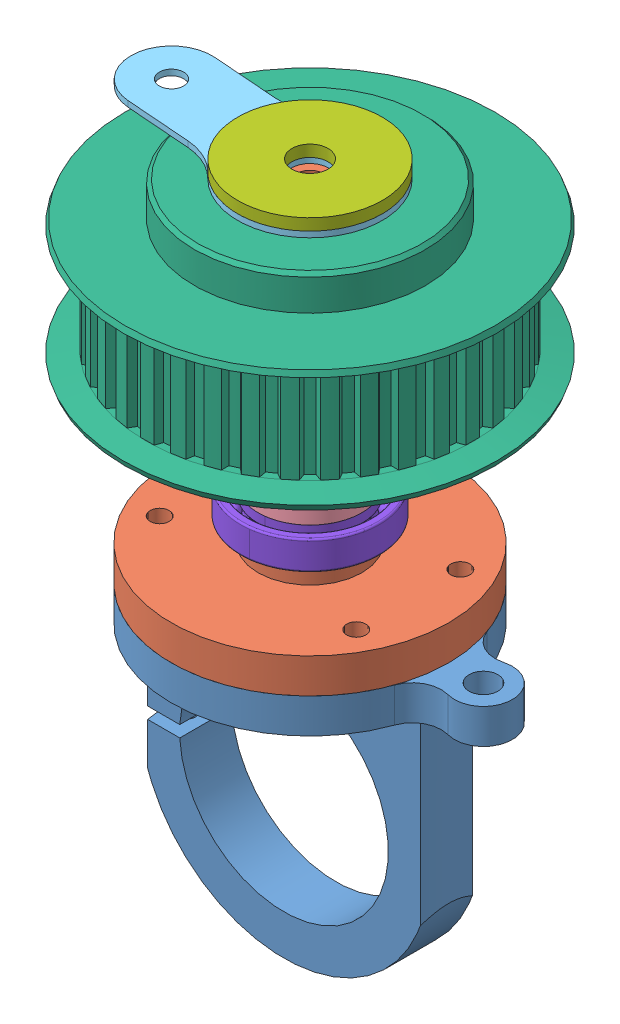
SolidWorks assembly B Axis, configuration Défaut. Lengths in mm.
Overall size (68.86 117.5 64.68).
9 component instances, 8 part files, 22 mates.
Components (placement in the parent):
- Spindle Housing v2-1: Spindle Housing v2 [Défaut] at (0 23 0) x (1 0 0) z (0 -1 0) size (59.51 48 54)
- B Axis-1: B Axis [Défaut] at (0 35 0) x (1 0 0) z (0 1 0) size (48 48 60)
- Bague B Axis_4.5mm v-2-1: Bague B Axis_4.5mm v-2 [Défaut] at (0 62.5 0) x (0.999992 0 -0.004028) z (0 -1 0) size (18 18 6.5)
- Bague Entretoise B axis bearing-1: Bague Entretoise B axis bearing [Défaut] at (0 51 0) x (0.946789 0 -0.321855) z (0 -1 0) size (18 18 7)
- Cale Axe B-1: Cale Axe B [Défaut] at (0 90.5 0) x (0.997118 0 0.075871) z (0 -1 0) size (45.5 25 1)
- pulley B Axis-1: pulley B Axis [Default] at (0 62.5 0) x (0 1 0) z (0 0 1) size (27 64.68 64.68)
- Rondelle B axis v-2-1: Rondelle B axis v-2 [Défaut] at (0 92.5 0) x (-0.97461 0 -0.223907) z (0 -1 0) size (25 25 2)
- 61802-1: 61802 [Défaut] at (0 44 0) x (0 -1 0) z (0.118563 0 0.992946) size (5 24 24)
- 61802-2: 61802 [Défaut] at (0 56 0) x (0 -1 0) z (-0.147702 0 0.989032) size (5 24 24)
Mates (geometry in assembly coordinates):
- Coincident6: coincident: plane of ? through (83.3313 -30.816 57.0781) normal (0 0 -1); plane of ? through (83.3313 -40.416 57.0781) normal (0 0 1)
- Coaxiale20: concentric anti-aligned: cylinder of Spindle Housing v2-1 through (0 29 0) axis (0 -1 0) radius 24; cylinder of B Axis-1 through (0 29 0) axis (0 1 0) radius 24
- Coïncidente11: coincident anti-aligned: plane of Spindle Housing v2-1 through (0 29 0) normal (0 1 0); plane of B Axis-1 through (0 29 0) normal (0 -1 0)
- Coaxiale21: concentric aligned: cylinder of B Axis-1 through (0 89 0) axis (0 -1 0) radius 7.5; cylinder of 61802-1 through (0 -56 0) axis (0 -1 0) radius 7.5
- Coaxiale22: concentric aligned: cylinder of B Axis-1 through (0 89 0) axis (0 -1 0) radius 7.5; cylinder of 61802-2 through (0 -44 0) axis (0 -1 0) radius 7.5
- Coaxiale23: concentric anti-aligned: cylinder of B Axis-1 through (0 89 0) axis (0 -1 0) radius 7.5; cylinder of Bague B Axis_4.5mm v-2-1 through (0 56 0) axis (0 1 0) radius 9
- Coaxiale24: concentric anti-aligned: cylinder of B Axis-1 through (0 89 0) axis (0 -1 0) radius 7.5; cylinder of Bague Entretoise B axis bearing-1 through (0 44 0) axis (0 1 0) radius 9
- Coaxiale25: concentric anti-aligned: cylinder of B Axis-1 through (0 89 0) axis (0 -1 0) radius 7.5; cylinder of Rondelle B axis v-2-1 through (0 90.5 0) axis (0 1 0) radius 3.125
- Coaxiale26: concentric anti-aligned: cylinder of B Axis-1 through (0 89 0) axis (0 -1 0) radius 7.5; cylinder of Cale Axe B-1 through (0 89.5 0) axis (0 1 0) radius 3.25
- Coïncidente12: coincident anti-aligned: plane of B Axis-1 through (0 39 0) normal (0 1 0); plane of 61802-1 through (7.745 39 -0.9248) normal (0 -1 0)
- Coaxiale27: concentric anti-aligned: cylinder of B Axis-1 through (0 89 0) axis (0 -1 0) radius 7.5; cylinder of pulley B Axis-1 through (0 62.5 0) axis (0 1 0) radius 7.5
- Coïncidente14: coincident aligned: plane of Spindle Housing v2-1 through (0 23 0) normal (0 0 1)
- Coïncidente15: coincident aligned: plane of Spindle Housing v2-1 through (0 23 0) normal (1 0 0)
- Distance4: distance = 0 mm: cylinder of Spindle Housing v2-1 through (0 0 4.5) axis (0 0 -1) radius 18.05
- Coaxiale28: concentric aligned: cylinder of Spindle Housing v2-1 through (17 23 -9) axis (0 -1 0) radius 4; cylinder of B Axis-1 through (17 29 -9) axis (0 -1 0) radius 1.65
- Coïncidente16: coincident aligned: plane of B Axis-1 through (-4.5 114 2.5) normal (0 0 -1); plane of pulley B Axis-1 through (0.2 11.403 2.5) normal (0 0 -1)
- Coïncidente17: coincident anti-aligned: plane of Cale Axe B-1 through (0 89.5 0) normal (0 -1 0); plane of pulley B Axis-1 through (0 89.5 0) normal (0 1 0)
- Coïncidente18: coincident anti-aligned: plane of Cale Axe B-1 through (0 90.5 0) normal (0 1 0); plane of Rondelle B axis v-2-1 through (0 90.5 0) normal (0 -1 0)
- Coïncidente19: coincident anti-aligned: plane of Bague Entretoise B axis bearing-1 through (0 44 0) normal (0 -1 0); plane of 61802-1 through (8.7379 44 -1.0434) normal (0 1 0)
- Coïncidente20: coincident anti-aligned: plane of Bague Entretoise B axis bearing-1 through (0 51 0) normal (0 1 0); plane of 61802-2 through (7.7144 51 1.1521) normal (0 -1 0)
- Coïncidente21: coincident anti-aligned: plane of Bague B Axis_4.5mm v-2-1 through (0 56 0) normal (0 -1 0); plane of 61802-2 through (8.7035 56 1.2998) normal (0 1 0)
- Coïncidente22: coincident anti-aligned: plane of Bague B Axis_4.5mm v-2-1 through (0 62.5 0) normal (0 1 0); plane of pulley B Axis-1 through (0 62.5 0) normal (0 -1 0)
